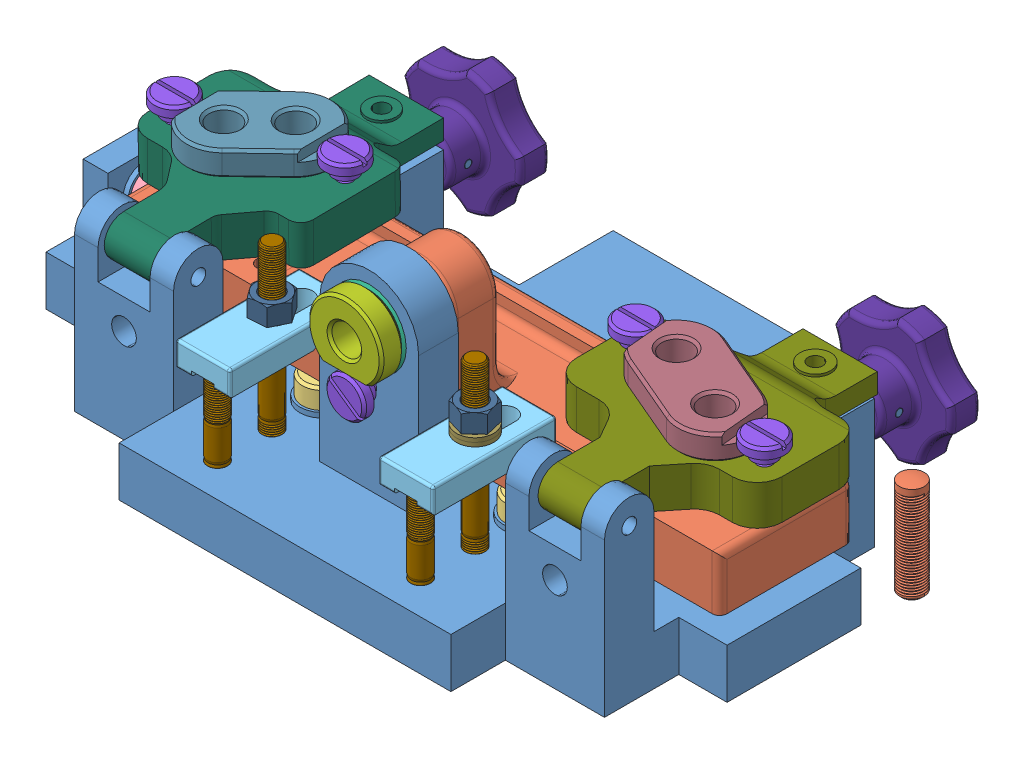
SolidWorks assembly 钻床夹具_3, configuration 默认. Lengths in mm.
Overall size (277.16 112.17 174).
41 component instances, 21 part files, 69 mates.
Components (placement in the parent):
- 钻床夹具（新）-1: 钻床夹具（新） [默认] at (32.8236 166.1356 213.2848) size (275 97 174)
- 前横架-1: 前横架 [默认] at (-90.6764 194.1356 161.2848) x (1 0 0) z (0 1 0) size (247 54 64)
- A型支承钉-1: A型支承钉 [默认] at (-8.1764 196.1356 157.2848) size (16 20 16)
- A型支承钉-2: A型支承钉 [默认] at (73.8236 196.1356 157.2848) size (16 20 16)
- A型支承钉-3: A型支承钉 [默认] at (32.8236 196.1356 110.2848) size (16 20 16)
- B型支承钉-1: B型支承钉 [默认] at (-90.6764 204.1356 136.2848) x (0 -1 0) z (0 0 1) size (16 20 16)
- B型支承钉-2: B型支承钉 [默认] at (119.8236 204.1356 161.2848) x (1 0 0) z (0 1 0) size (16 20 16)
- B型支承钉-3: B型支承钉 [默认] at (-54.1764 204.1356 161.2848) x (1 0 0) z (0 1 0) size (16 20 16)
- A8×50移动压板-5: A8×50移动压板 [默认] at (-19.1764 216.1356 155.5348) x (0 0 1) z (-1 0 0) size (50 10 22)
- A8×50移动压板-6: A8×50移动压板 [默认] at (62.8236 216.1356 155.5348) x (0 0 1) z (-1 0 0) size (50 10 22)
- 零件3^钻床夹具_3-1: 零件3^钻床夹具_3 [默认] at origin (virtual)
- 衬套-1: 衬套 [默认] at (32.8236 243.1356 163.2848) x (1 0 0) z (0 -1 0) size (30 16 30)
- 可换钻套-1: 可换钻套 [默认] at (32.8236 243.1356 163.2848) x (0 -1 0) z (-1 0 0) size (30 26 30)
- 钻套螺钉M6×4-1: 钻套螺钉M6×4 [默认] at (32.8236 223.1356 171.2848) x (0.819152 -0.573576 0) z (-0.573576 -0.819152 0) size (16 18 16)
- double end studs bm=2d gb-1: double end studs bm=2d gb [GB_FASTENER_BOLT_DESB20 A M8X60-S] at (-8.1764 176.1356 177.5348) x (0 1 0) z (0.766872 0 0.6418) size (76 8 8)
- double end studs bm=2d gb-2: double end studs bm=2d gb [GB_FASTENER_BOLT_DESB20 A M8X60-S] at (73.8236 176.1356 177.5348) x (0 1 0) z (-0.617114 0 0.786874) size (76 8 8)
- hex nut-fine pitch-style washer-grade ab gb-1: hex nut-fine pitch-style washer-grade ab gb [GB_HEXAGON_TYPE10_1 M8X1-N] at (-8.1764 226.7356 177.5348) x (-0.997148 0 0.075465) z (0 -1 0) size (15.01 13 8.1)
- hex nut-fine pitch-style washer-grade ab gb-2: hex nut-fine pitch-style washer-grade ab gb [GB_HEXAGON_TYPE10_1 M8X1-S] at (73.8236 229.9356 177.5348) x (0.229012 0 0.973424) z (0 -1 0) size (15.01 13 8.1)
- plain washers-n series-grade a gb-1: plain washers-n series-grade a gb [GB_FASTENER_WASHER_PWNA 8] at (73.8236 216.1356 177.5348) x (1 0 0) z (0 1 0) size (16 16 1.6)
- plain washers-n series-grade a gb-2: plain washers-n series-grade a gb [GB_FASTENER_WASHER_PWNA 8] at (-8.1764 216.1356 177.5348) x (1 0 0) z (0 1 0) size (16 16 1.6)
- plain washers-s series-grade a gb-1: plain washers-s series-grade a gb [GB_FASTENER_WASHER_PWSA 8] at (73.8236 227.7356 177.5348) x (1 0 0) z (0 -1 0) size (15 15 1.6)
- plain washers-s series-grade a gb-2: plain washers-s series-grade a gb [GB_FASTENER_WASHER_PWSA 8] at (73.8236 226.1356 177.5348) x (1 0 0) z (0 -1 0) size (15 15 1.6)
- 特殊钻套1-1: 特殊钻套1 [默认] at (132.4791 220.1356 139.2849) x (0.99593 0 -0.090128) z (0 1 0) size (56 44 26)
- 特殊钻套2-1: 特殊钻套2 [默认] at (-65.6764 220.6012 139.1987) x (1 0 0) z (0 0.999939 0.011074) size (45 44 26)
- 钻模板小-1: 钻模板小 [默认] at (-65.6764 220.6012 139.1987) x (1 0 0) z (0 -0.011074 0.999939) size (71 16 112)
- 钻模板大-1: 钻模板大 [默认] at (132.4791 220.1356 139.2849) size (83 16 112)
- 钻套螺钉M6×4-2: 钻套螺钉M6×4 [默认] at (86.4791 228.1356 125.2849) size (16 18 16)
- 钻套螺钉M6×4-4: 钻套螺钉M6×4 [默认] at (152.4791 228.1356 139.2849) size (16 18 16)
- 钻套螺钉M6×4-5: 钻套螺钉M6×4 [默认] at (-85.6764 228.6007 139.2873) x (1 0 0) z (0 -0.011074 0.999939) size (16 18 16)
- 钻套螺钉M6×4-6: 钻套螺钉M6×4 [默认] at (-30.6764 228.7557 125.2882) x (1 0 0) z (0 -0.011074 0.999939) size (16 18 16)
- double end studs bm=2d gb-3: double end studs bm=2d gb [GB_FASTENER_BOLT_DESB20 A M8X30-S] at (-8.1764 172.1356 199.5348) x (0 1 0) z (0.766872 0 0.6418) size (46 8 8)
- double end studs bm=2d gb-4: double end studs bm=2d gb [GB_FASTENER_BOLT_DESB20 A M8X30-S] at (73.8236 172.1356 199.5348) x (0 1 0) z (0.766872 0 0.6418) size (46 8 8)
- 单螺旋夹紧_星形把手-2: 单螺旋夹紧_星形把手 [默认] at (148.0319 200.0317 96.6847) x (-1 0 0) z (0 0 -1) size (47.87 49.9 63.11)
  - BM10星形把手-1: BM10星形把手 [默认] at (28.2083 4.1039 52.3999) x (0 1 0) z (0 0 1) size (49.9 47.87 26.11)
  - AM10×60压紧螺钉-1: AM10×60压紧螺钉 [默认] at (28.2083 4.1039 49.3999) size (10.14 11.55 59.97)
  - parallel pins hardening steel gb-2: parallel pins hardening steel gb [GB_CONNECTING_PIECE_PIN_DP 3X22] at (17.2083 4.1039 33.3999) x (1 0 0) z (0 0.764188 0.644994) size (22 3 3)
- 单螺旋夹紧_星形把手-3: 单螺旋夹紧_星形把手 [默认] at (-25.9681 200.0317 96.6847) x (-1 0 0) z (0 0 -1) size (47.87 49.9 63.11)
  - BM10星形把手-1: BM10星形把手 [默认] at (28.2083 4.1039 52.3999) x (0 1 0) z (0 0 1) size (49.9 47.87 26.11)
  - AM10×60压紧螺钉-1: AM10×60压紧螺钉 [默认] at (28.2083 4.1039 49.3999) size (10.14 11.55 59.97)
  - parallel pins hardening steel gb-2: parallel pins hardening steel gb [GB_CONNECTING_PIECE_PIN_DP 3X22] at (17.2083 4.1039 33.3999) x (1 0 0) z (0 0.764188 0.644994) size (22 3 3)
- 辅助支撑螺柱-1: 辅助支撑螺柱 [默认] at (142.8569 163.621 70.1913) size (10 40 10)
Mates (geometry in assembly coordinates):
- 同心1: concentric: cylinder of assembly; cylinder of assembly; cylinder of 钻床夹具（新）-1 through (-8.1764 173.1356 157.2848) axis (0 1 0) radius 5; cylinder of A型支承钉-1 through (-8.1764 176.1356 157.2848) axis (0 -1 0) radius 5
- 重合1: coincident: plane of assembly; plane of assembly; plane of 钻床夹具（新）-1 through (-8.1764 188.1356 157.2848) normal (0 1 0); plane of A型支承钉-1 through (-0.1764 188.1356 157.2848) normal (0 -1 0)
- 重合2: coincident: plane of assembly; plane of assembly; plane of 钻床夹具（新）-1 through (32.8236 188.1356 110.2848) normal (0 1 0); plane of A型支承钉-3 through (40.8236 188.1356 110.2848) normal (0 -1 0)
- 同心2: concentric: cylinder of assembly; cylinder of assembly; cylinder of 钻床夹具（新）-1 through (32.8236 173.1356 110.2848) axis (0 1 0) radius 5; cylinder of A型支承钉-3 through (32.8236 176.1356 110.2848) axis (0 -1 0) radius 5
- 重合3: coincident: plane of assembly; plane of assembly; plane of 钻床夹具（新）-1 through (73.8236 188.1356 157.2848) normal (0 1 0); plane of A型支承钉-2 through (81.8236 188.1356 157.2848) normal (0 -1 0)
- 同心3: concentric: cylinder of assembly; cylinder of assembly; cylinder of 钻床夹具（新）-1 through (73.8236 173.1356 157.2848) axis (0 1 0) radius 5; cylinder of A型支承钉-2 through (73.8236 176.1356 157.2848) axis (0 -1 0) radius 5
- 重合4: coincident: plane of assembly; plane of assembly; plane of 钻床夹具（新）-1 through (-54.1764 204.1356 169.2848) normal (0 0 -1); plane of B型支承钉-3 through (-46.1764 204.1356 169.2848) normal (0 0 1)
- 同心4: concentric: cylinder of assembly; cylinder of assembly; cylinder of 钻床夹具（新）-1 through (-54.1764 204.1356 213.2858) axis (0 0 -1) radius 5; cylinder of B型支承钉-3 through (-54.1764 204.1356 181.2848) axis (0 0 1) radius 5
- 同心5: concentric: cylinder of assembly; cylinder of assembly; cylinder of 钻床夹具（新）-1 through (-115.6774 204.1356 136.2848) axis (1 0 0) radius 5; cylinder of B型支承钉-1 through (-110.6764 204.1356 136.2848) axis (-1 0 0) radius 5
- 重合5: coincident: plane of assembly; plane of assembly; plane of 钻床夹具（新）-1 through (-98.6764 204.1356 136.2848) normal (1 0 0); plane of B型支承钉-1 through (-98.6764 196.1356 136.2848) normal (-1 0 0)
- 同心6: concentric: cylinder of assembly; cylinder of assembly; cylinder of 钻床夹具（新）-1 through (119.8236 204.1356 213.2858) axis (0 0 -1) radius 5; cylinder of B型支承钉-2 through (119.8236 204.1356 181.2848) axis (0 0 1) radius 5
- 重合6: coincident: plane of assembly; plane of assembly; plane of 钻床夹具（新）-1 through (119.8236 204.1356 169.2848) normal (0 0 -1); plane of B型支承钉-2 through (127.8236 204.1356 169.2848) normal (0 0 1)
- 重合7: coincident: plane of assembly; plane of assembly; plane of A型支承钉-1 through (-8.1764 196.1356 157.2848) normal (0 1 0); plane of 前横架-1 through (-90.6764 196.1356 161.2848) normal (0 -1 0)
- 相切2: tangent: sphere of assembly; plane of assembly; sphere of B型支承钉-3; plane of 前横架-1 through (-90.6764 216.1356 161.2848) normal (0 0 1)
- 相切3: tangent: sphere of assembly; plane of assembly; sphere of B型支承钉-2; plane of 前横架-1 through (-90.6764 216.1356 161.2848) normal (0 0 1)
- 相切4: tangent: sphere of assembly; plane of assembly; sphere of B型支承钉-1; plane of 前横架-1 through (-90.6764 216.1356 161.2848) normal (-1 0 0)
- 重合10: coincident: plane of assembly; plane of assembly; plane of 前横架-1 through (-90.6764 216.1356 161.2848) normal (0 1 0); plane of A8×50移动压板-5 through (-19.1764 216.1356 155.5348) normal (0 -1 0)
- 重合11: coincident: plane of assembly; plane of assembly; plane of 前横架-1 through (-90.6764 216.1356 161.2848) normal (0 1 0); plane of A8×50移动压板-6 through (62.8236 216.1356 155.5348) normal (0 -1 0)
- 同心8: concentric: cylinder of assembly; cylinder of assembly; cylinder of 钻床夹具（新）-1 through (-8.1764 166.1356 177.5348) axis (0 1 0) radius 4; cylinder of A8×50移动压板-5 through (-8.1764 226.1356 177.5348) axis (0 -1 0) radius 4.5
- 同心9: concentric: cylinder of assembly; cylinder of assembly; cylinder of 钻床夹具（新）-1 through (73.8236 166.1356 177.5348) axis (0 1 0) radius 4; cylinder of A8×50移动压板-6 through (73.8236 226.1356 177.5348) axis (0 -1 0) radius 4.5
- 同心10: concentric: cylinder of assembly; cylinder of assembly; cylinder of 钻床夹具（新）-1 through (32.8236 243.1356 39.2838) axis (0 0 1) radius 13; cylinder of 衬套-1 through (32.8236 243.1356 179.2848) axis (0 0 1) radius 13
- 重合12: coincident: plane of assembly; plane of assembly; plane of 钻床夹具（新）-1 through (32.8236 243.1356 176.2848) normal (0 0 1); plane of 衬套-1 through (44.8236 243.1356 176.2848) normal (0 0 -1)
- 同心11: concentric: cylinder of assembly; cylinder of assembly; cylinder of 衬套-1 through (32.8236 243.1356 163.2848) axis (0 0 1) radius 9; cylinder of 可换钻套-1 through (32.8236 243.1356 189.2848) axis (0 0 1) radius 9
- 重合13: coincident: plane of assembly; plane of assembly; plane of 衬套-1 through (47.8236 243.1356 179.2848) normal (0 0 1); plane of 可换钻套-1 through (32.8236 243.1356 179.2848) normal (0 0 -1)
- 同心12: concentric: cylinder of assembly; cylinder of assembly; cylinder of 钻床夹具（新）-1 through (32.8236 223.1356 167.2848) axis (0 0 1) radius 3; cylinder of 钻套螺钉M6×4-1 through (32.8236 223.1356 189.2848) axis (0 0 1) radius 3
- 重合14: coincident: plane of assembly; plane of assembly; plane of 可换钻套-1 through (32.8236 243.1356 185.2848) normal (0 0 1); plane of 钻套螺钉M6×4-1 through (36.7146 220.4111 185.2848) normal (0 0 -1)
- 平行1: parallel: plane of assembly; plane of assembly; plane of 钻床夹具（新）-1 through (32.8236 186.1356 213.2848) normal (0 1 0); plane of 可换钻套-1 through (43.0217 232.1356 185.2848) normal (0 -1 0)
- 同心13: concentric: circle of assembly; cylinder of assembly; circle of 钻床夹具（新）-1; cylinder of double end studs bm=2d gb-2 through (73.8236 174.8248 177.5348) axis (0 -1 0) radius 4
- 同心14: concentric: cylinder of assembly; cylinder of assembly; cylinder of 钻床夹具（新）-1 through (-8.1764 166.1356 177.5348) axis (0 1 0) radius 4; cylinder of double end studs bm=2d gb-1 through (-8.1764 174.8248 177.5348) axis (0 -1 0) radius 4
- 同心16: concentric: cylinder of assembly; cylinder of assembly; cylinder of double end studs bm=2d gb-2 through (73.8236 174.8248 177.5348) axis (0 -1 0) radius 4; cylinder of hex nut-fine pitch-style washer-grade ab gb-2 through (73.8236 237.4356 177.5348) axis (0 -1 0) radius 3.4585
- 同心18: concentric: cylinder of assembly; cylinder of assembly; cylinder of double end studs bm=2d gb-1 through (-8.1764 174.8248 177.5348) axis (0 -1 0) radius 4; cylinder of hex nut-fine pitch-style washer-grade ab gb-1 through (-8.1764 234.2356 177.5348) axis (0 -1 0) radius 3.4585
- 距离1: distance = 10 mm: plane of assembly; plane of assembly; plane of double end studs bm=2d gb-1 through (-8.1764 176.1356 177.5348) normal (0 -1 0); plane of 钻床夹具（新）-1 through (32.8236 186.1356 213.2848) normal (0 1 0)
- 距离2: distance = 10 mm: plane of assembly; plane of assembly; plane of 钻床夹具（新）-1 through (32.8236 186.1356 213.2848) normal (0 1 0); plane of double end studs bm=2d gb-2 through (73.8236 176.1356 177.5348) normal (0 -1 0)
- 重合20: coincident: plane of assembly; plane of assembly; plane of A8×50移动压板-5 through (-19.1764 226.1356 155.5348) normal (0 1 0); plane of hex nut-fine pitch-style washer-grade ab gb-1 through (-8.1764 226.1356 177.5348) normal (0 -1 0)
- 同心21: concentric: cylinder of assembly; cylinder of assembly; cylinder of double end studs bm=2d gb-2 through (73.8236 174.8248 177.5348) axis (0 -1 0) radius 4; cylinder of plain washers-n series-grade a gb-1 through (73.8236 214.5356 177.5348) axis (0 1 0) radius 4.2
- 重合25: coincident: plane of assembly; plane of assembly; plane of A8×50移动压板-6 through (62.8236 216.1356 155.5348) normal (0 -1 0); plane of plain washers-n series-grade a gb-1 through (73.8236 216.1356 177.5348) normal (0 1 0)
- 同心23: concentric: cylinder of assembly; cylinder of assembly; cylinder of double end studs bm=2d gb-1 through (-8.1764 174.8248 177.5348) axis (0 -1 0) radius 4; cylinder of plain washers-n series-grade a gb-2 through (-8.1764 214.5356 177.5348) axis (0 1 0) radius 4.2
- 重合26: coincident: plane of assembly; plane of assembly; plane of A8×50移动压板-5 through (-19.1764 216.1356 155.5348) normal (0 -1 0); plane of plain washers-n series-grade a gb-2 through (-8.1764 216.1356 177.5348) normal (0 1 0)
- 重合27: coincident: plane of assembly; plane of assembly; plane of A8×50移动压板-6 through (62.8236 226.1356 155.5348) normal (0 1 0); plane of plain washers-s series-grade a gb-2 through (73.8236 226.1356 177.5348) normal (0 -1 0)
- 同心24: concentric: cylinder of assembly; cylinder of assembly; cylinder of double end studs bm=2d gb-2 through (73.8236 174.8248 177.5348) axis (0 -1 0) radius 4; cylinder of plain washers-s series-grade a gb-2 through (73.8236 227.7356 177.5348) axis (0 -1 0) radius 4.2
- 重合29: coincident: plane of assembly; plane of assembly; plane of plain washers-s series-grade a gb-1 through (73.8236 227.7356 177.5348) normal (0 -1 0); plane of plain washers-s series-grade a gb-2 through (73.8236 227.7356 177.5348) normal (0 1 0)
- 同心25: concentric: cylinder of assembly; cylinder of assembly; cylinder of double end studs bm=2d gb-2 through (73.8236 174.8248 177.5348) axis (0 -1 0) radius 4; cylinder of plain washers-s series-grade a gb-1 through (73.8236 229.3356 177.5348) axis (0 -1 0) radius 4.2
- 重合30: coincident: plane of assembly; plane of assembly; plane of hex nut-fine pitch-style washer-grade ab gb-2 through (73.8236 229.3356 177.5348) normal (0 -1 0); plane of plain washers-s series-grade a gb-1 through (73.8236 229.3356 177.5348) normal (0 1 0)
- 同心29: concentric: cylinder of assembly; cylinder of assembly; cylinder of 前横架-1 through (105.3231 194.1356 127.6853) axis (0 1 0) radius 6; cylinder of 特殊钻套1-1 through (105.3231 246.1356 127.6853) axis (0 -1 0) radius 6
- 平行6: parallel: cylinder of assembly; cylinder of assembly; cylinder of 前横架-1 through (131.3236 194.1356 141.2848) axis (0 1 0) radius 6; cylinder of 特殊钻套1-1 through (132.4791 246.1356 139.2849) axis (0 -1 0) radius 6
- 同心32: concentric: cylinder of assembly; cylinder of assembly; cylinder of 特殊钻套1-1 through (132.4791 246.1356 139.2849) axis (0 -1 0) radius 6; cylinder of 钻模板大-1 through (132.4791 236.1356 139.2849) axis (0 -1 0) radius 9
- 同心33: concentric: cylinder of assembly; cylinder of assembly; cylinder of 特殊钻套2-1 through (-50.6764 246.7546 125.4875) axis (0 -0.999939 -0.011074) radius 6; cylinder of 钻模板小-1 through (-50.6764 236.7552 125.3768) axis (0 -0.999939 -0.011074) radius 9
- 同心34: concentric: cylinder of assembly; cylinder of assembly; cylinder of 特殊钻套2-1 through (-65.6764 246.5996 139.4867) axis (0 -0.999939 -0.011074) radius 6; cylinder of 钻模板小-1 through (-65.6764 236.6002 139.3759) axis (0 -0.999939 -0.011074) radius 9
- 重合34: coincident: plane of assembly; plane of assembly; plane of 特殊钻套2-1 through (-65.6764 236.6002 139.3759) normal (0 -0.999939 -0.011074); plane of 钻模板小-1 through (-65.6764 236.6002 139.3759) normal (0 0.999939 0.011074)
- 重合35: coincident: plane of assembly; plane of assembly; plane of 特殊钻套1-1 through (132.4791 236.1356 139.2849) normal (0 -1 0); plane of 钻模板大-1 through (132.4791 236.1356 139.2849) normal (0 1 0)
- 同心35: concentric: cylinder of assembly; cylinder of assembly; cylinder of 钻模板大-1 through (86.4791 236.1356 125.2849) axis (0 -1 0) radius 3; cylinder of 钻套螺钉M6×4-2 through (86.4791 246.1356 125.2849) axis (0 1 0) radius 3
- 重合38: coincident: plane of assembly; plane of assembly; plane of 特殊钻套1-1 through (105.3231 242.1356 127.6853) normal (0 1 0); plane of 钻套螺钉M6×4-2 through (91.2291 242.1356 125.2849) normal (0 -1 0)
- 同心36: concentric: cylinder of assembly; cylinder of assembly; cylinder of 钻模板大-1 through (152.4791 236.1356 139.2849) axis (0 -1 0) radius 3; cylinder of 钻套螺钉M6×4-4 through (152.4791 246.1356 139.2849) axis (0 1 0) radius 3
- 重合39: coincident: plane of assembly; plane of assembly; plane of 特殊钻套1-1 through (132.4791 242.1356 139.2849) normal (0 1 0); plane of 钻套螺钉M6×4-4 through (157.2291 242.1356 139.2849) normal (0 -1 0)
- 同心37: concentric: cylinder of assembly; cylinder of assembly; cylinder of 钻模板小-1 through (-30.6764 236.7552 125.3768) axis (0 -0.999939 -0.011074) radius 3; cylinder of 钻套螺钉M6×4-6 through (-30.6764 246.7546 125.4875) axis (0 0.999939 0.011074) radius 3
- 重合40: coincident: plane of assembly; plane of assembly; plane of 特殊钻套2-1 through (-50.6764 242.7549 125.4432) normal (0 0.999939 0.011074); plane of 钻套螺钉M6×4-6 through (-25.9264 242.7549 125.4432) normal (0 -0.999939 -0.011074)
- 重合42: coincident: plane of assembly; plane of assembly; plane of 特殊钻套2-1 through (-65.6764 242.5998 139.4424) normal (0 0.999939 0.011074); plane of 钻套螺钉M6×4-5 through (-80.9264 242.5998 139.4424) normal (0 -0.999939 -0.011074)
- 同心38: concentric: cylinder of assembly; cylinder of assembly; cylinder of 钻模板小-1 through (-85.6764 236.6002 139.3759) axis (0 -0.999939 -0.011074) radius 3; cylinder of 钻套螺钉M6×4-5 through (-85.6764 246.5996 139.4867) axis (0 0.999939 0.011074) radius 3
- 同心41: concentric: cylinder of assembly; cylinder of assembly; cylinder of 钻床夹具（新）-1 through (73.8236 166.1356 199.5348) axis (0 1 0) radius 4; cylinder of double end studs bm=2d gb-4 through (73.8236 170.8248 199.5348) axis (0 -1 0) radius 4
- 重合43: coincident: plane of assembly; plane of assembly; plane of A8×50移动压板-6 through (73.8236 218.1356 165.5348) normal (0 -1 0); plane of double end studs bm=2d gb-4 through (71.2564 218.1356 202.6022) normal (0 1 0)
- 同心42: concentric: cylinder of assembly; cylinder of assembly; cylinder of 钻床夹具（新）-1 through (-8.1764 166.1356 199.5348) axis (0 1 0) radius 4; cylinder of double end studs bm=2d gb-3 through (-8.1764 170.8248 199.5348) axis (0 -1 0) radius 4
- 重合44: coincident: plane of assembly; plane of assembly; plane of A8×50移动压板-5 through (-8.1764 218.1356 165.5348) normal (0 -1 0); plane of double end studs bm=2d gb-3 through (-10.7436 218.1356 202.6022) normal (0 1 0)
- 同心43: concentric: cylinder of assembly; cylinder of assembly; cylinder of 钻床夹具（新）-1 through (91.3384 228.1356 181.2848) axis (1 0 0) radius 3; cylinder of 钻模板大-1 through (110.9791 228.1356 181.2848) axis (1 0 0) radius 3
- 同心45: concentric: cylinder of assembly; cylinder of assembly; cylinder of 钻床夹具（新）-1 through (-25.6911 228.1356 181.2848) axis (-1 0 0) radius 3; cylinder of 钻模板小-1 through (-93.6774 228.1356 181.2848) axis (1 0 0) radius 3
- 距离3: distance = 0.5 mm: plane of assembly; plane of assembly; plane of 钻模板小-1 through (-64.1764 236.3234 164.3744) normal (-1 0 0); plane of 钻床夹具（新）-1 through (-64.6764 228.1356 213.2848) normal (1 0 0)
- 同心46: concentric: cylinder of assembly; cylinder of assembly; cylinder of 钻床夹具（新）-1 through (119.8236 204.1356 39.2838) axis (0 0 1) radius 5; cylinder of 单螺旋夹紧_星形把手-2/AM10×60压紧螺钉-1 through (119.8236 204.1356 47.2848) axis (0 0 -1) radius 3.5
- 相切5: tangent: plane of assembly; sphere of assembly; plane of 前横架-1 through (-90.6764 216.1356 107.2848) normal (0 0 -1); sphere of 单螺旋夹紧_星形把手-2/AM10×60压紧螺钉-1
- 同心47: concentric: cylinder of assembly; cylinder of assembly; cylinder of 钻床夹具（新）-1 through (-54.1764 204.1356 39.2838) axis (0 0 1) radius 5; cylinder of 单螺旋夹紧_星形把手-3/AM10×60压紧螺钉-1 through (-54.1764 204.1356 47.2848) axis (0 0 -1) radius 3.5
- 相切6: tangent: plane of assembly; sphere of assembly; plane of 前横架-1 through (-90.6764 216.1356 107.2848) normal (0 0 -1); sphere of 单螺旋夹紧_星形把手-3/AM10×60压紧螺钉-1
